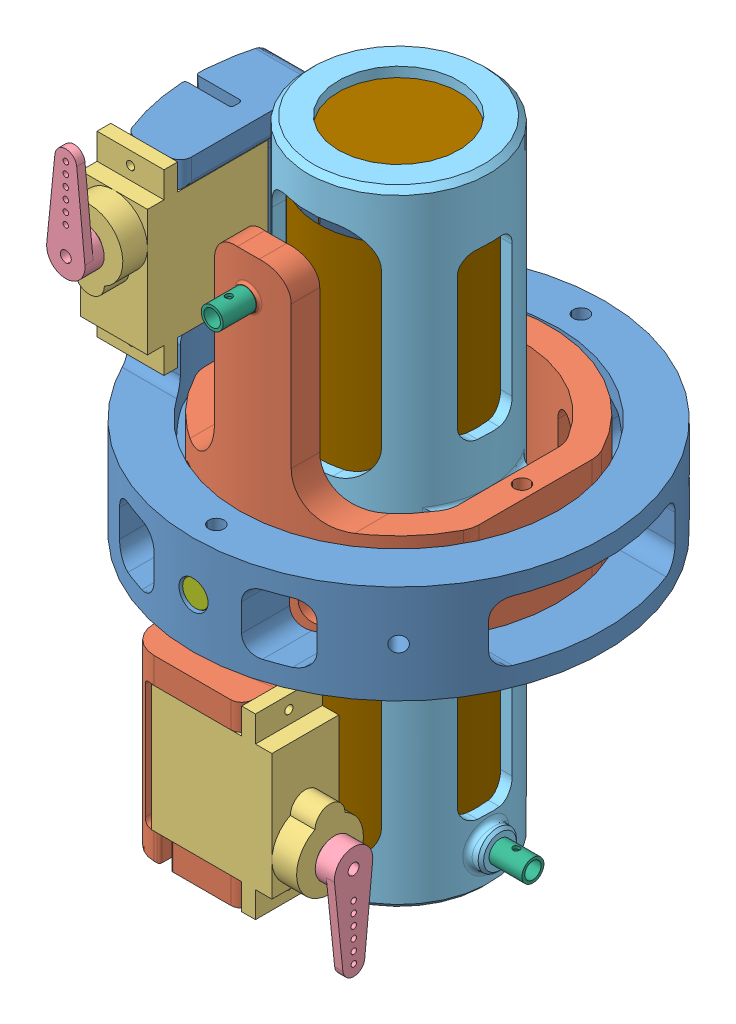
SolidWorks assembly Assemblage TVC, configuration Défaut. Lengths in mm.
Overall size (75 114 75).
15 component instances, 10 part files, 34 mates.
Components (placement in the parent):
- Cardan roulis-1: Cardan roulis [Défaut] at origin size (75 53.5 75)
- Cardan tangage-1: Cardan tangage [Défaut] at origin size (50 96.5 63.11)
- SG90-1: SG90 [Défaut] at (-31.4 28.25 9.5) size (12.2 32.5 29.3)
- Biellette-1: Biellette [Défaut] at (-31.4 33.65 29.3) x (-1 0 0) z (0 0 -1) size (7 20.5 3.5)
- Support moteur-1: Support moteur [Défaut] at origin size (40 114 33)
- SG90-2: SG90 [Défaut] at (1.5 -31.25 29.5139) x (0 0 1) z (1 0 0) size (12.2 32.5 29.3)
- Biellette-2: Biellette [Défaut] at (21.3 -36.65 29.5139) x (0 0.002642 -0.999997) z (-1 0 0) size (7 20.5 3.5)
- Pivot-1: Pivot [Défaut] at (0 42 28.5) x (-0.99999 0.004378 0) z (0 0 -1) size (4 4 11)
- Pivot-2: Pivot [Défaut] at (19 -50 0) x (0 0.007842 0.999969) z (-1 0 0) size (4 4 11)
- Axe roulis-1: Axe roulis [Défaut] at (0 0 30.75) x (0.930758 0.365636 0) z (0 0 1) size (5 5 12.5)
- Axe tangage-1: Axe tangage [Défaut] at (20.5 0 0) x (0 0.408481 -0.912767) z (1 0 0) size (5 5 9)
- Axe roulis-2: Axe roulis [Défaut] at (0 0 -30.75) x (0.930758 0.365636 0) z (0 0 1) size (5 5 12.5)
- Axe tangage-2: Axe tangage [Défaut] at (-20.5 0 0) x (0 0.408481 -0.912767) z (1 0 0) size (5 5 9)
- Chambre combustion-1: Chambre combustion [Défaut] at (0 -4.7182 0) x (-1 0 0) z (0 -1 0) size (29 29 111.84)
- Bouchon-1: Bouchon [Défaut] at (0 43.5 0) x (1 0 0) z (0 1 0) size (29 29 23.58)
Mates (geometry in assembly coordinates):
- Coïncidente1: coincident aligned: plane of Cardan roulis-1 through (0 0 0) normal (0 0 1); plane of assembly through (0 0 0) normal (0 0 1)
- Coïncidente2: coincident aligned: plane of Cardan roulis-1 through (0 0 0) normal (0 1 0); plane of assembly through (0 0 0) normal (0 1 0)
- Coïncidente3: coincident aligned: plane of Cardan roulis-1 through (0 0 0) normal (1 0 0); plane of assembly through (0 0 0) normal (1 0 0)
- Coïncidente4: coincident aligned: plane of Cardan roulis-1 through (0 0 0) normal (0 0 1); plane of Cardan tangage-1 through (0 0 0) normal (0 0 1)
- Coaxiale1: concentric aligned: cylinder of Cardan roulis-1 through (0 0 -37.501) axis (0 0 1) radius 2.65; cylinder of Cardan tangage-1 through (0 0 24.5) axis (0 0 1) radius 2.5
- Coïncidente6: coincident anti-aligned: plane of SG90-1 through (-31.4 33.65 27.8) normal (0 0 1); plane of Biellette-1 through (-31.4 33.65 27.8) normal (0 0 -1)
- Coaxiale2: concentric aligned: cylinder of SG90-1 through (-31.4 33.65 27.8) axis (0 0 -1) radius 2.45; cylinder of Biellette-1 through (-31.4 33.65 27.8) axis (0 0 -1) radius 2.45
- Coïncidente8: coincident aligned: plane of Cardan tangage-1 through (0 0 0) normal (1 0 0); plane of Support moteur-1 through (0 0 0) normal (1 0 0)
- Coaxiale3: concentric aligned: cylinder of Cardan tangage-1 through (-25.001 0 0) axis (1 0 0) radius 2.65; cylinder of Support moteur-1 through (16 0 0) axis (1 0 0) radius 2.65
- Coïncidente9: coincident anti-aligned: plane of Cardan roulis-1 through (-34.3693 44.5 15) normal (0 0 1); plane of SG90-1 through (-25.3 39.75 15) normal (0 0 -1)
- Coïncidente15: coincident anti-aligned: plane of Cardan roulis-1 through (37.501 16.75 15) normal (0 1 0); plane of SG90-1 through (-25.3 16.75 -1.5) normal (0 -1 0)
- Tangent1: tangent aligned: cylinder of Cardan roulis-1 through (0 9 0) axis (0 -1 0) radius 37.5; plane of SG90-1 through (-37.5 28.25 9.5) normal (-1 0 0)
- Parallèle4: parallel anti-aligned: plane of Biellette-1 through (-31.4 33.65 29.3) normal (-1 0 0); plane of assembly through (0 0 0) normal (1 0 0)
- Coïncidente20: coincident anti-aligned: plane of Cardan tangage-1 through (7 -42.75 23.4139) normal (0 1 0); plane of SG90-2 through (-9.5 -42.75 35.6139) normal (0 -1 0)
- Coïncidente22: coincident anti-aligned: plane of Cardan tangage-1 through (0 0 23.4139) normal (0 0 1); plane of SG90-2 through (1.5 -31.25 23.4139) normal (0 0 -1)
- Coïncidente24: coincident anti-aligned: plane of SG90-2 through (7 -19.75 35.6139) normal (-1 0 0); plane of Cardan tangage-1 through (7 -15 26.5942) normal (1 0 0)
- Coïncidente25: coincident anti-aligned: plane of SG90-2 through (19.8 -36.65 29.5139) normal (1 0 0); plane of Biellette-2 through (19.8 -36.65 29.5139) normal (-1 0 0)
- Coaxiale4: concentric aligned: cylinder of SG90-2 through (19.8 -36.65 29.5139) axis (-1 0 0) radius 2.45; cylinder of Biellette-2 through (19.8 -36.65 29.5139) axis (-1 0 0) radius 2.45
- Coaxiale5: concentric anti-aligned: cylinder of Cardan tangage-1 through (0 42 -27.5) axis (0 0 1) radius 1.05; cylinder of Pivot-1 through (0 42 23) axis (0 0 -1) radius 1
- Coïncidente26: coincident anti-aligned: plane of Cardan tangage-1 through (0 42 28) normal (0 0 1); plane of Pivot-1 through (0.0044 43 28) normal (0 0 -1)
- Coaxiale6: concentric anti-aligned: cylinder of Support moteur-1 through (-20.001 -50 0) axis (1 0 0) radius 1.05; cylinder of Pivot-2 through (13.5 -50 0) axis (-1 0 0) radius 1
- Coïncidente27: coincident anti-aligned: plane of Support moteur-1 through (18.5 -50 0) normal (1 0 0); plane of Pivot-2 through (18.5 -49 -0.0078) normal (-1 0 0)
- Coaxiale7: concentric anti-aligned: cylinder of Cardan roulis-1 through (0 0 -37.501) axis (0 0 1) radius 2.65; cylinder of Axe roulis-1 through (0 0 37) axis (0 0 -1) radius 2.5
- Coïncidente28: coincident anti-aligned: plane of Cardan tangage-1 through (0 0 24.5) normal (0 0 1); plane of Axe roulis-1 through (0 0 24.5) normal (0 0 -1)
- Coaxiale9: concentric anti-aligned: cylinder of Cardan tangage-1 through (-25.001 0 0) axis (1 0 0) radius 2.65; cylinder of Axe tangage-1 through (25 0 0) axis (-1 0 0) radius 2.5
- Coïncidente29: coincident anti-aligned: plane of Support moteur-1 through (16 0 0) normal (1 0 0); plane of Axe tangage-1 through (16 0 0) normal (-1 0 0)
- Parallèle6: parallel aligned: plane of Cardan roulis-1 through (0 9 0) normal (0 1 0); plane of Support moteur-1 through (0 57 0) normal (0 1 0)
- Coaxiale10: concentric aligned: cylinder of Support moteur-1 through (0 57 0) axis (0 -1 0) radius 14.5; cylinder of Chambre combustion-1 through (0 -56.6363 0) axis (0 -1 0) radius 14.5
- Coïncidente31: coincident anti-aligned: plane of Support moteur-1 through (0 0 0) normal (1 0 0); plane of Chambre combustion-1 through (0 -4.7182 0) normal (-1 0 0)
- Coaxiale11: concentric anti-aligned: cylinder of Chambre combustion-1 through (0 -56.6363 0) axis (0 -1 0) radius 14.5; cylinder of Bouchon-1 through (0 55 0) axis (0 1 0) radius 14.5
- Coïncidente33: coincident anti-aligned: plane of Chambre combustion-1 through (0 -4.7182 0) normal (-1 0 0); plane of Bouchon-1 through (0 43.5 0) normal (1 0 0)
- Coïncidente34: coincident anti-aligned: plane of Chambre combustion-1 through (0 47 14.5) normal (0 1 0); plane of Bouchon-1 through (0 47 -14.5) normal (0 -1 0)
- Coïncidente35: coincident anti-aligned: plane of Support moteur-1 through (0 55 0) normal (0 -1 0); plane of Bouchon-1 through (0 55 0) normal (0 1 0)
- Parallèle8: parallel aligned: plane of Cardan tangage-1; plane of Support moteur-1
